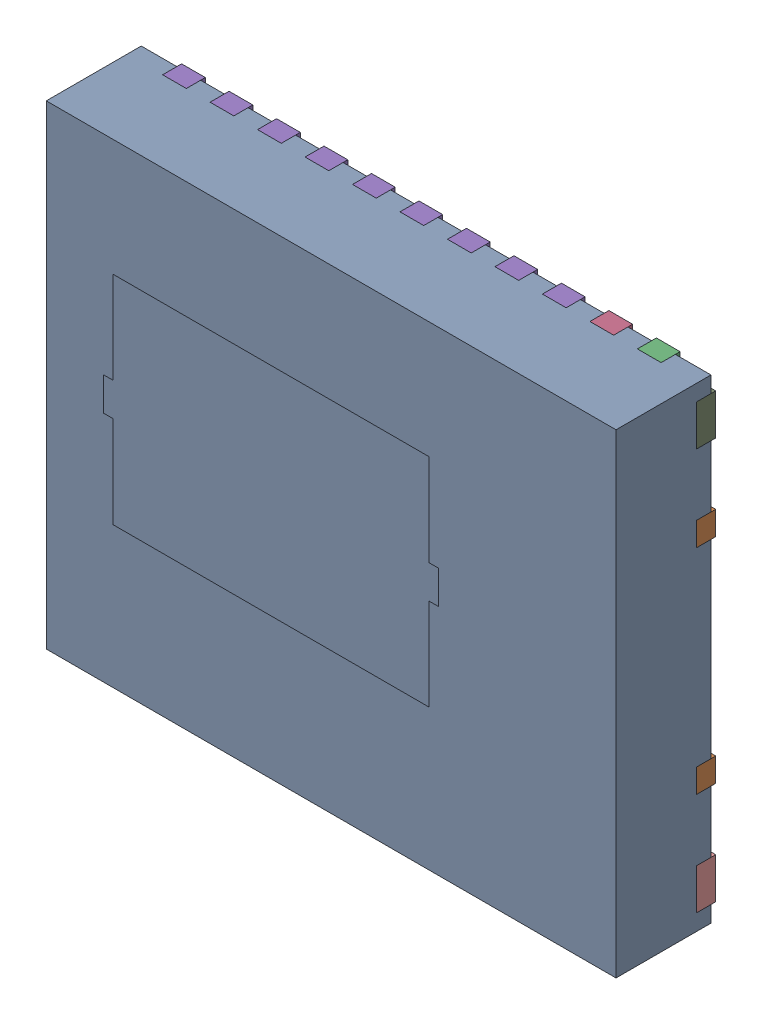
SolidWorks assembly U4, configuration Default. Lengths in mm.
Overall size (6 5 1.05).
15 component instances, 13 part files, 0 mates.
Components (placement in the parent):
- DMM0022A-1: DMM0022A [Default] at (15.7481 42.5449 0) x (0 -1 0) z (0 0 1) size (5 6 1.05)
  - BODY-SON-1: BODY-SON [Default] at (0 0 0.05) x (1 0 0) z (0 -1 0) size (5 1 6)
  - FRAME-DMM0022A-1: FRAME-DMM0022A [Default] x (1 0 0) z (0 -1 0) size (5 0.2 6)
    - Open CASCADE STEP translator 7.5 1.2.1.2.1-1: Open CASCADE STEP translator 7.5 1.2.1.2.1 [Default] at origin size (3.5 0.2 6)
    - Open CASCADE STEP translator 7.5 1.2.1.2.2-1: Open CASCADE STEP translator 7.5 1.2.1.2.2 [Default] at origin size (0.5 0.2 0.25)
    - Open CASCADE STEP translator 7.5 1.2.1.2.3-1: Open CASCADE STEP translator 7.5 1.2.1.2.3 [Default] at origin size (0.5 0.2 0.25)
    - Open CASCADE STEP translator 7.5 1.2.1.2.4-1: Open CASCADE STEP translator 7.5 1.2.1.2.4 [Default] at origin size (0.5 0.2 4.25)
    - Open CASCADE STEP translator 7.5 1.2.1.2.5-1: Open CASCADE STEP translator 7.5 1.2.1.2.5 [Default] at origin size (0.5 0.2 0.25)
    - Open CASCADE STEP translator 7.5 1.2.1.2.6-1: Open CASCADE STEP translator 7.5 1.2.1.2.6 [Default] at origin size (0.5 0.2 0.25)
    - Open CASCADE STEP translator 7.5 1.2.1.2.7-1: Open CASCADE STEP translator 7.5 1.2.1.2.7 [Default] at origin size (0.5 0.2 4.25)
    - Open CASCADE STEP translator 7.5 1.2.1.2.8-1: Open CASCADE STEP translator 7.5 1.2.1.2.8 [Default] at origin size (0.43 0.2 0.18)
    - Open CASCADE STEP translator 7.5 1.2.1.2.9-1: Open CASCADE STEP translator 7.5 1.2.1.2.9 [Default] at origin size (0.43 0.2 0.18)
    - Open CASCADE STEP translator 7.5 1.2.1.2.10-1: Open CASCADE STEP translator 7.5 1.2.1.2.10 [Default] at origin size (0.43 0.2 0.18)
    - Open CASCADE STEP translator 7.5 1.2.1.2.11-1: Open CASCADE STEP translator 7.5 1.2.1.2.11 [Default] at origin size (0.43 0.2 0.18)
  - HEATSLUG-1: HEATSLUG [Default] at (-0.128 -0.635 0.958) x (1 0 0) z (0 -1 0) size (2.28 0.09 3.53)
